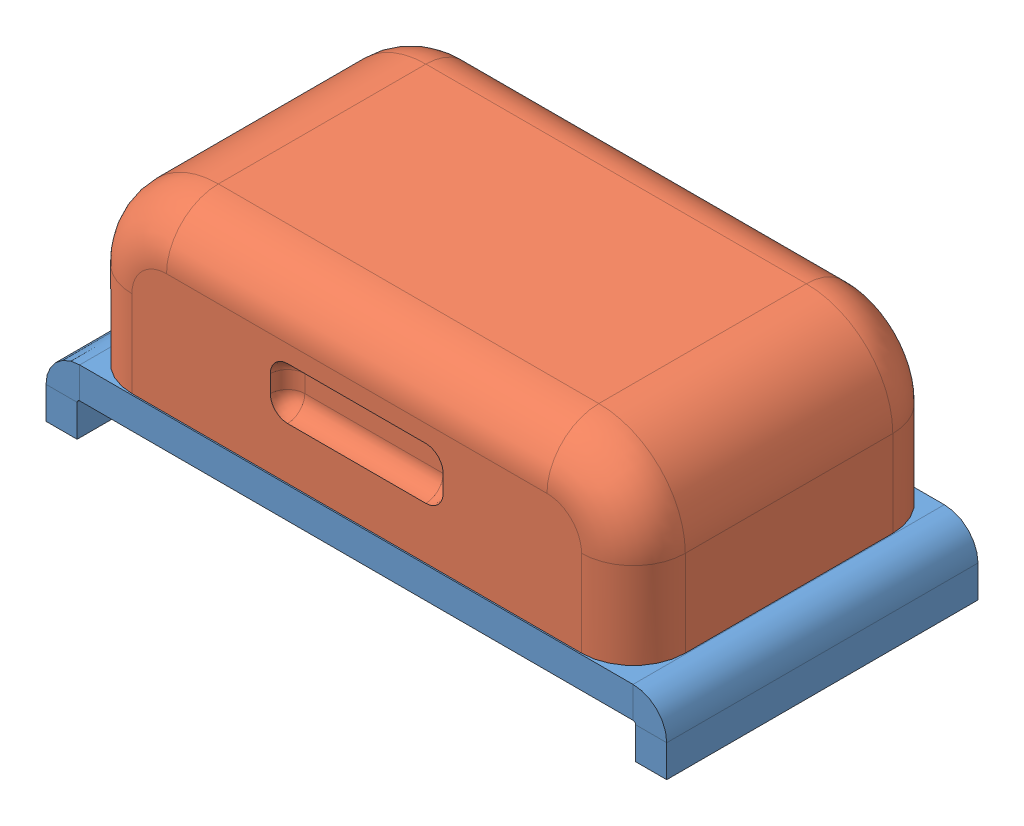
SolidWorks assembly Assemblage1, configuration Défaut. Lengths in mm.
Overall size (192.04 74.14 96.39).
2 component instances, 2 part files, 0 mates.
Components (placement in the parent):
- base tôle-1: base tôle [Défaut] at (-27.8829 -17.5981 -11.3397) size (192.04 24.61 96.3)
- couvercle-1: couvercle [Défaut] at (-90.1055 -5.7664 -4.5515) size (171.2 53.5 96.3)
